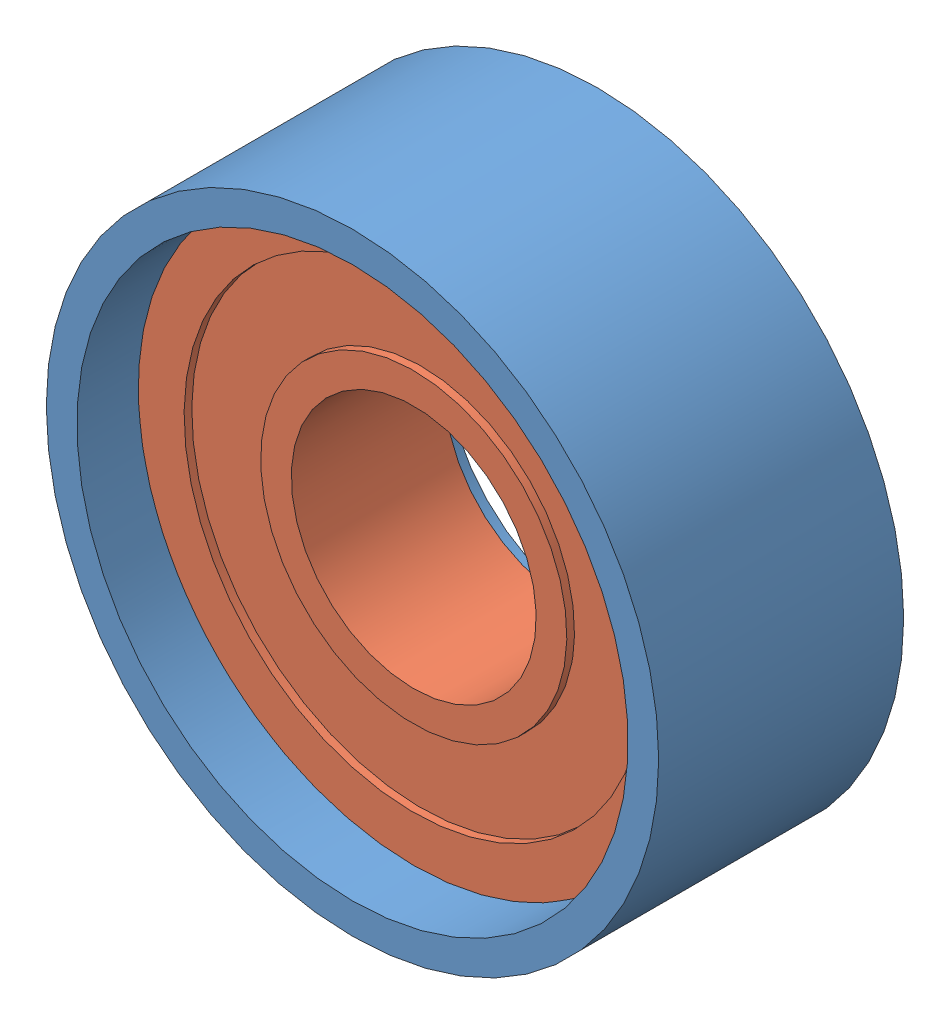
SolidWorks assembly bearing block outer, configuration Default. Lengths in mm.
Overall size (32.39 32.39 12.7).
2 component instances, 2 part files, 0 mates.
Components (placement in the parent):
- bearing block outer-1-1: bearing block outer-1 [Default] at origin size (31.75 31.75 12.7)
- R8-ZZ-12-1: R8-ZZ-12 [Default] at (0 0 -0.7937) x (0.9896 -0.143847 0) z (0 0 -1) size (28.57 28.57 7.94)
